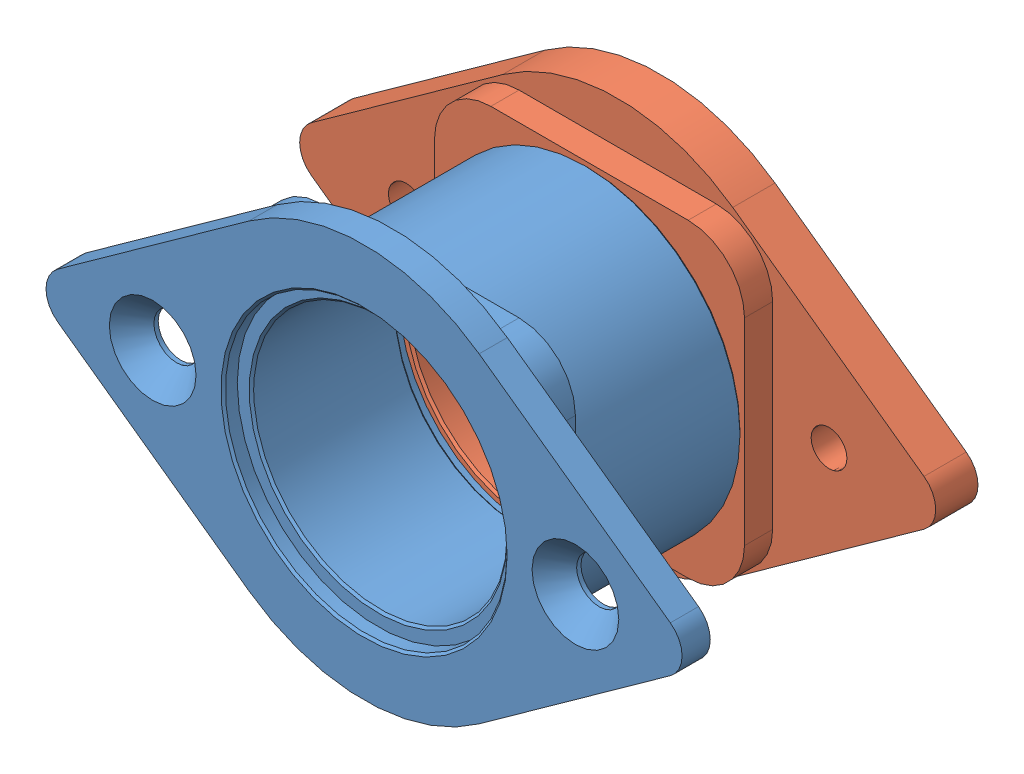
SolidWorks assembly WCP_Side_Bearing_Block_Kit_217-3436 (1), configuration Default. Lengths in mm.
Overall size (71.66 44.45 33.34).
2 component instances, 2 part files, 0 mates.
Components (placement in the parent):
- 217-3436-001 Rev2-1: 217-3436-001 Rev2 [Default] at origin size (71.66 44.45 25.15)
- 217-3436-002 Rev2-1: 217-3436-002 Rev2 [Default] at (0 0 -29.3687) x (-1 0 0) z (0 0 -1) size (71.66 44.45 14.29)
